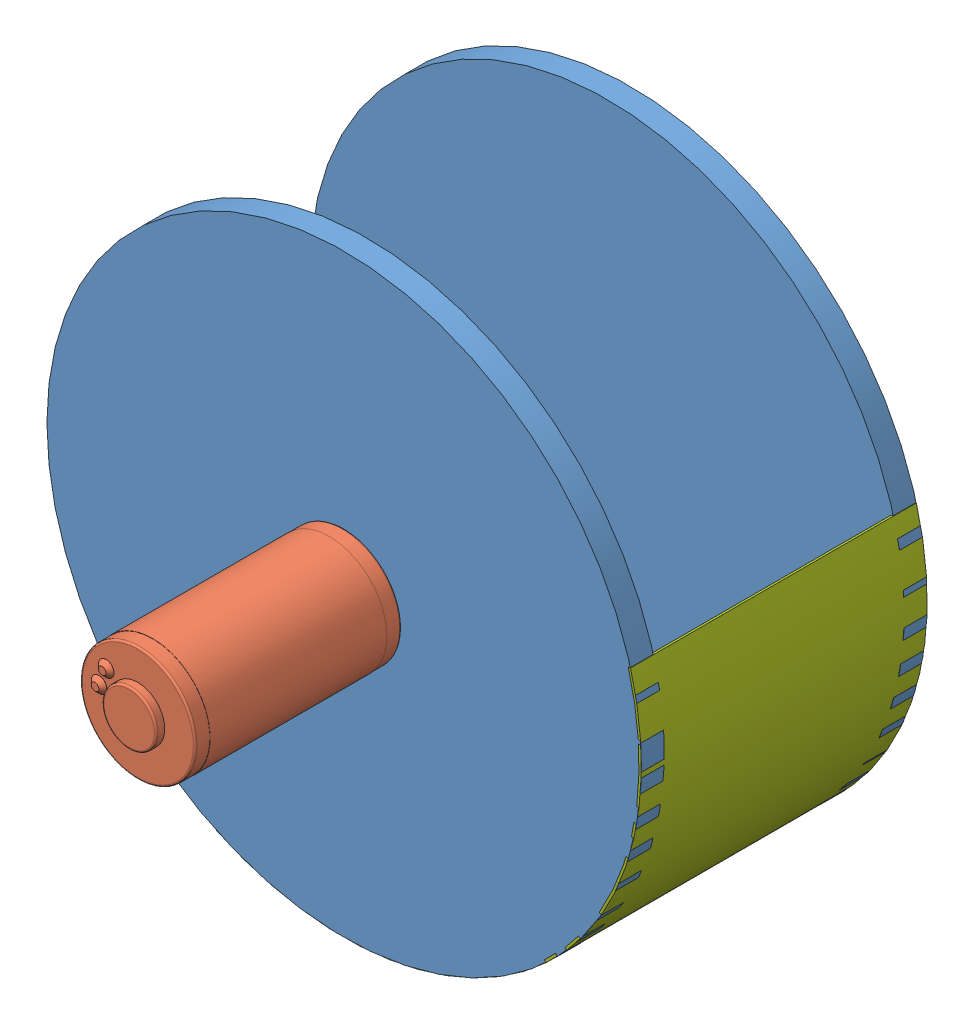
SolidWorks assembly Shooter, configuration Default. Lengths in mm.
Overall size (436.31 436.31 278.12).
9 component instances, 7 part files, 12 mates.
Components (placement in the parent):
- ShooterSide-1: ShooterSide [Default] at (135.3447 148.7785 259.7287) size (330.12 330.12 12.7)
- ShooterSide-2: ShooterSide [Default] at (66.8911 173.9601 113.6787) x (-0.912439 -0.409213 0) z (0 0 1) size (330.12 330.12 12.7)
- 2.5in CIM Motor-1: 2.5in CIM Motor [Default] at (178.5256 81.3542 291.4787) x (-0.923728 -0.383049 0) z (0 0 -1) size (64.01 64.01 154.93)
- 4 in HiGrip Wheel-1: 4 in HiGrip Wheel [Default] at (106.3463 166.1694 210.0842) x (0 0 1) z (-1 0 0) size (35.12 101.6 101.6)
  - 4 in tread-1: 4 in tread [Default] at (-8.0517 2.5236 2.5343) size (25.4 101.6 101.6)
  - 4in 2013 Hub-1: 4in 2013 Hub [Default] at (-8.0517 2.5236 2.5343) size (35.12 82.55 82.55)
- am-0077a-500 Key Hub r2-1: am-0077a-500 Key Hub r2 [Default] at (103.812 168.693 237.5037) x (-0.911507 -0.411285 0) z (0 0 -1) size (57.15 57.15 25.4)
- ShooterSpacer-1: ShooterSpacer [Default] at (109.3928 167.1815 219.4951) size (63.75 63.75 12.7)
- ShooterRamp-1: ShooterRamp [Default] at (74.6576 145.4353 272.4287) x (-0.993949 -0.109844 0) z (0 0 -1) size (251.99 191.46 158.75)
Mates (geometry in assembly coordinates):
- Concentric1: concentric aligned: cylinder of ShooterSide-1 through (103.812 168.693 272.4287) axis (0 0 -1) radius 165.0623; cylinder of ShooterSide-2 through (88.3765 240.5504 139.6212) axis (0 0 -1) radius 165.0623
- Coincident3: coincident anti-aligned: plane of ShooterSide-1 through (103.812 168.693 272.4287) normal (0 0 1); plane of 2.5in CIM Motor-1 through (103.812 168.693 272.4287) normal (0 0 -1)
- Concentric2: concentric aligned: circle of 2.5in CIM Motor-1; circle of am-0077a-500 Key Hub r2-1
- Concentric3: concentric aligned: cylinder of ShooterSide-1 through (103.812 168.693 272.4287) axis (0 0 -1) radius 165.0623; cylinder of 2.5in CIM Motor-1 through (103.812 168.693 387.0335) axis (0 0 -1) radius 31.877
- Distance2: distance = 3.175 mm anti-aligned: plane of ShooterSide-1 through (103.812 168.693 259.7287) normal (0 0 -1); plane of am-0077a-500 Key Hub r2-1 through (103.812 168.693 256.5537) normal (0 0 1)
- Coincident7: coincident anti-aligned: circle of am-0077a-500 Key Hub r2-1; plane of ShooterSpacer-1 through (103.812 168.693 232.1951) normal (0 0 1)
- Concentric4: concentric anti-aligned: cylinder of am-0077a-500 Key Hub r2-1 through (103.812 168.693 231.1537) axis (0 0 1) radius 28.575; cylinder of ShooterSpacer-1 through (103.812 168.693 232.1951) axis (0 0 -1) radius 31.8767
- Coincident8: coincident anti-aligned: plane of 4 in HiGrip Wheel-1/4in 2013 Hub-1 through (103.812 168.693 219.4951) normal (0 0 1); plane of ShooterSpacer-1 through (103.812 168.693 219.4951) normal (0 0 -1)
- Concentric5: concentric anti-aligned: cylinder of 4 in HiGrip Wheel-1/4in 2013 Hub-1 through (103.812 168.693 212.5101) axis (0 0 1) radius 14.2875; cylinder of ShooterSpacer-1 through (103.812 168.693 232.1951) axis (0 0 -1) radius 31.8767
- Concentric8: concentric anti-aligned: cylinder of ShooterSide-1 through (103.812 168.693 272.4287) axis (0 0 -1) radius 165.0623; cylinder of ShooterRamp-1 through (103.812 168.693 113.6787) axis (0 0 1) radius 163.7923
- Coincident9: coincident aligned: plane of ShooterSide-1 through (103.812 168.693 272.4287) normal (0 0 1); plane of ShooterRamp-1 through (103.812 168.693 272.4287) normal (0 0 1)
- Coincident10: coincident aligned: plane of ShooterSide-2 through (103.812 168.693 113.6787) normal (0 0 -1); plane of ShooterRamp-1 through (103.812 168.693 113.6787) normal (0 0 -1)
